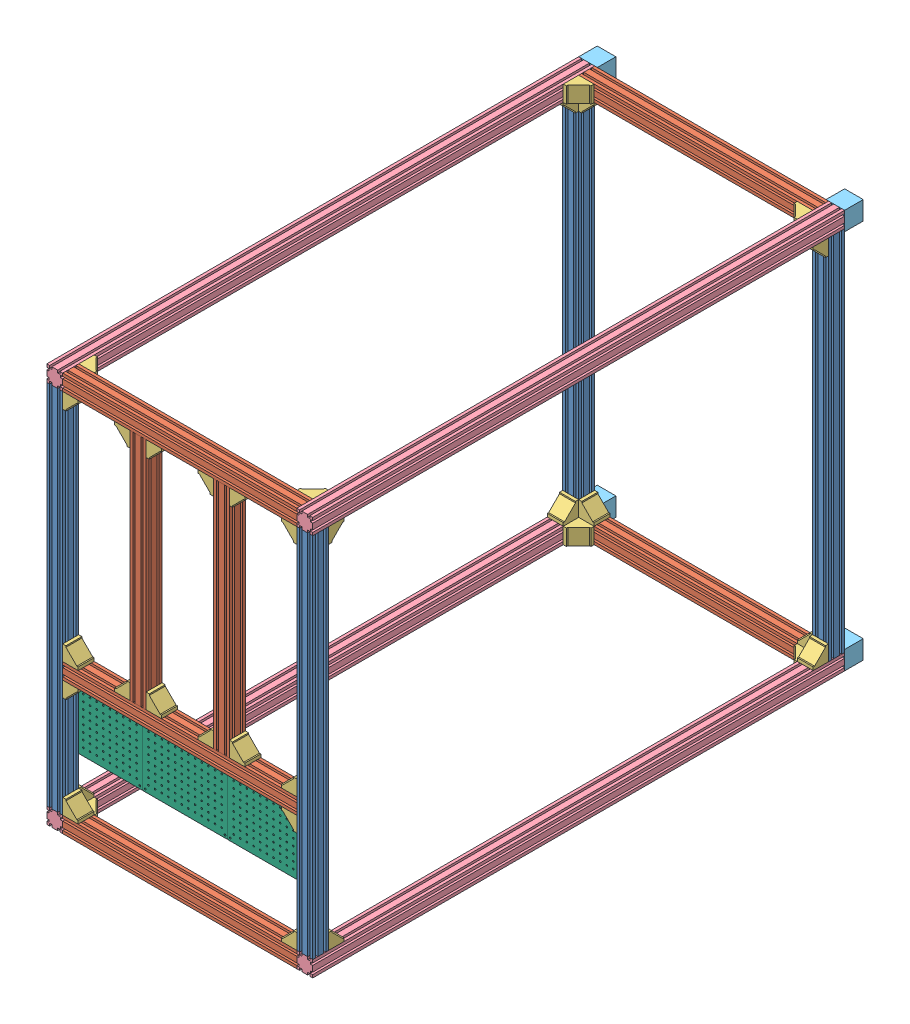
SolidWorks assembly 4轮平台张1.0, configuration 默认. Lengths in mm.
Overall size (1020 1500 2070).
59 component instances, 6 part files, 9 mates.
Components (placement in the parent):
- 框架-1: 框架 [默认] at (-507.7096 31.3488 3075) size (1000 1500 2070)
  - 框架（水平 大）-1: 框架（水平 大） [默认] at (-98.7964 -668.0959 30) size (60 1380 60)
  - 框架（水平 大）-2: 框架（水平 大） [默认] at (841.2036 -668.0959 30) size (60 1380 60)
  - 框架（水平 小）-1: 框架（水平 小） [默认] at (841.2036 711.9041 30) x (0 1 0) z (0 0 1) size (60 880 60)
  - 框架（水平 小）-2: 框架（水平 小） [默认] at (841.2036 -228.0959 30) x (0 1 0) z (0 0 1) size (60 880 60)
  - 框架（水平 小）-6: 框架（水平 小） [默认] at (841.2036 -728.0959 30) x (0 1 0) z (0 0 1) size (60 880 60)
  - 外角件-1: 外角件 [默认] at (-38.7964 -668.0959 -30) size (58 58 60)
  - 外角件-2: 外角件 [默认] at (841.2036 -668.0959 -30) x (0 1 0) z (0 0 1) size (58 58 60)
  - 外角件-3: 外角件 [默认] at (841.2036 -228.0959 -30) x (-1 0 0) z (0 0 1) size (58 58 60)
  - 外角件-4: 外角件 [默认] at (-38.7964 -228.0959 30) x (1 0 0) z (0 0 -1) size (58 58 60)
  - 外角件-5: 外角件 [默认] at (-38.7964 -168.0959 -30) size (58 58 60)
  - 外角件-6: 外角件 [默认] at (527.8703 -168.0959 -30) x (0 1 0) z (0 0 1) size (58 58 60)
  - 外角件-7: 外角件 [默认] at (-38.7964 711.9041 -30) x (0 -1 0) z (0 0 1) size (58 58 60)
  - 外角件-8: 外角件 [默认] at (527.8703 711.9041 30) x (0 -1 0) z (0 0 -1) size (58 58 60)
  - 外角件-9: 外角件 [默认] at (587.8703 -168.0959 -30) size (58 58 60)
  - 外角件-10: 外角件 [默认] at (841.2036 -168.0959 -30) x (0 1 0) z (0 0 1) size (58 58 60)
  - 外角件-11: 外角件 [默认] at (587.8703 711.9041 -30) x (0 -1 0) z (0 0 1) size (58 58 60)
  - 外角件-12: 外角件 [默认] at (841.2036 711.9041 -30) x (-1 0 0) z (0 0 1) size (58 58 60)
  - 框架（竖直）-1: 框架（竖直） [默认] at (-38.7964 771.9041 30) x (0 -1 0) z (1 0 0) size (60 2000 60)
  - 框架（竖直）-2: 框架（竖直） [默认] at (901.2036 711.9041 30) x (-1 0 0) z (0 -1 0) size (60 2000 60)
  - 框架（竖直）-3: 框架（竖直） [默认] at (-98.7964 -728.0959 -1970) x (1 0 0) z (0 -1 0) size (60 2000 60)
  - 框架（竖直）-4: 框架（竖直） [默认] at (841.2036 -668.0959 30) x (1 0 0) z (0 1 0) size (60 2000 60)
  - 框架（水平 小）-7: 框架（水平 小） [默认] at (841.2036 711.9041 -1970) x (0 0 1) z (0 -1 0) size (60 880 60)
  - 框架（水平 小）-8: 框架（水平 小） [默认] at (-38.7964 -668.0959 -1910) x (0 -1 0) z (0 0 1) size (60 880 60)
  - 框架（水平 大）-3: 框架（水平 大） [默认] at (901.2036 -668.0959 -1910) x (0 0 -1) z (1 0 0) size (60 1380 60)
  - 框架（水平 大）-4: 框架（水平 大） [默认] at (-98.7964 -668.0959 -1910) size (60 1380 60)
  - 外角件-13: 外角件 [默认] at (-38.7964 -668.0959 -1970) size (58 58 60)
  - 外角件-14: 外角件 [默认] at (841.2036 711.9041 -1970) x (-1 0 0) z (0 0 1) size (58 58 60)
  - 外角件-15: 外角件 [默认] at (841.2036 -668.0959 -1970) x (0 1 0) z (0 0 1) size (58 58 60)
  - 外角件-16: 外角件 [默认] at (-38.7964 711.9041 -1910) x (1 0 0) z (0 0 -1) size (58 58 60)
  - 外角件-17: 外角件 [默认] at (-98.7964 711.9041 -30) x (0 -1 0) z (1 0 0) size (58 58 60)
  - 外角件-18: 外角件 [默认] at (841.2036 -668.0959 -30) x (0 0 -1) z (1 0 0) size (58 58 60)
  - 外角件-19: 外角件 [默认] at (-38.7964 711.9041 -1910) x (0 -1 0) z (-1 0 0) size (58 58 60)
  - 外角件-20: 外角件 [默认] at (901.2036 -668.0959 -1910) x (0 0 1) z (-1 0 0) size (58 58 60)
  - 外角件-21: 外角件 [默认] at (841.2036 711.9041 -30) x (0 -1 0) z (1 0 0) size (58 58 60)
  - 外角件-22: 外角件 [默认] at (841.2036 771.9041 -1910) x (0 0 1) z (0 -1 0) size (58 58 60)
  - 外角件-23: 外角件 [默认] at (-98.7964 -668.0959 -30) x (0 0 -1) z (1 0 0) size (58 58 60)
  - 外角件-24: 外角件 [默认] at (-38.7964 -668.0959 -1910) x (0 0 1) z (-1 0 0) size (58 58 60)
  - 外角件-25: 外角件 [默认] at (841.2036 -668.0959 -1910) x (0 0 1) z (0 -1 0) size (58 58 60)
  - 外角件-26: 外角件 [默认] at (-38.7964 -728.0959 -30) x (1 0 0) z (0 1 0) size (58 58 60)
  - 外角件-27: 外角件 [默认] at (841.2036 -728.0959 -30) x (0 0 -1) z (0 1 0) size (58 58 60)
  - 外角件-28: 外角件 [默认] at (-38.7964 711.9041 -30) x (1 0 0) z (0 1 0) size (58 58 60)
  - 外角件-29: 外角件 [默认] at (-38.7964 -668.0959 -1910) x (1 0 0) z (0 -1 0) size (58 58 60)
  - 外角件-30: 外角件 [默认] at (841.2036 711.9041 -1910) x (0 0 1) z (1 0 0) size (58 58 60)
  - 外角件-31: 外角件 [默认] at (-38.7964 711.9041 -1910) x (0 0 1) z (0 1 0) size (58 58 60)
  - 外角件-32: 外角件 [默认] at (841.2036 711.9041 -30) x (0 0 -1) z (0 1 0) size (58 58 60)
  - 框架（水平 小）-9: 框架（水平 小） [默认] at (527.8703 -168.0959 30) size (60 880 60)
  - 框架（水平 小）-10: 框架（水平 小） [默认] at (214.537 -168.0959 30) size (60 880 60)
  - 外角件-33: 外角件 [默认] at (274.537 711.9041 -30) x (0 -1 0) z (0 0 1) size (58 58 60)
  - 外角件-34: 外角件 [默认] at (214.537 711.9041 -30) x (-1 0 0) z (0 0 1) size (58 58 60)
  - 外角件-35: 外角件 [默认] at (274.537 -168.0959 -30) size (58 58 60)
  - 外角件-36: 外角件 [默认] at (214.537 -168.0959 -30) x (0 1 0) z (0 0 1) size (58 58 60)
  - 支脚-1: 支脚 [默认] at (831.2036 -728.0959 -1970) size (70 70 70)
  - 支脚-2: 支脚 [默认] at (-98.7964 -728.0959 -1970) size (70 70 70)
  - 支脚-3: 支脚 [默认] at (-98.7964 701.9041 -1970) size (70 70 70)
  - 支脚-4: 支脚 [默认] at (831.2036 701.9041 -1970) size (70 70 70)
- 定位板-1: 定位板 [默认] at (173.4941 -325.847 3035) x (1 0 0) z (0 -1 0) size (320 10 280)
- 定位板-2: 定位板 [默认] at (-146.5059 -325.847 3035) x (1 0 0) z (0 -1 0) size (320 10 280)
- 定位板-3: 定位板 [默认] at (-466.5059 -325.847 3035) x (1 0 0) z (0 -1 0) size (320 10 280)
Mates (geometry in assembly coordinates):
- 重合3: coincident: line of 框架-1/框架（水平 小）-2 through (-546.5059 -185.847 3045) axis (1 0 0); line of 定位板-1 through (236.2531 -185.847 3045) axis (-1 0 0)
- 重合4: coincident: plane of 框架-1/框架（水平 小）-2 through (-546.5059 -196.747 3045) normal (0 0 -1); plane of 定位板-1 through (80.2531 -325.847 3045) normal (0 0 1)
- 重合5: coincident anti-aligned: plane of 框架-1/框架（水平 大）-2 through (333.4941 743.253 3105) normal (-1 0 0); plane of 定位板-1 through (333.4941 -465.847 3045) normal (1 0 0)
- 重合6: coincident: plane of 框架-1/框架（水平 小）-2 through (-546.5059 -196.747 3045) normal (0 0 -1); plane of 定位板-2 through (-146.5059 -325.847 3045) normal (0 0 1)
- 重合7: coincident: line of 框架-1/框架（水平 小）-2 through (-546.5059 -185.847 3045) axis (1 0 0); line of 定位板-2 through (9.4941 -185.847 3045) axis (-1 0 0)
- 重合8: coincident anti-aligned: plane of 定位板-1 through (13.4941 -465.847 3045) normal (-1 0 0); plane of 定位板-2 through (13.4941 -465.847 3045) normal (1 0 0)
- 重合9: coincident: plane of 框架-1/框架（水平 小）-2 through (-546.5059 -196.747 3045) normal (0 0 -1); plane of 定位板-3 through (-466.5059 -325.847 3045) normal (0 0 1)
- 重合10: coincident: line of 框架-1/框架（水平 小）-2 through (-546.5059 -185.847 3045) axis (1 0 0); line of 定位板-3 through (-310.5059 -185.847 3045) axis (-1 0 0)
- 重合11: coincident anti-aligned: plane of 定位板-2 through (-306.5059 -465.847 3045) normal (-1 0 0); plane of 定位板-3 through (-306.5059 -465.847 3045) normal (1 0 0)
